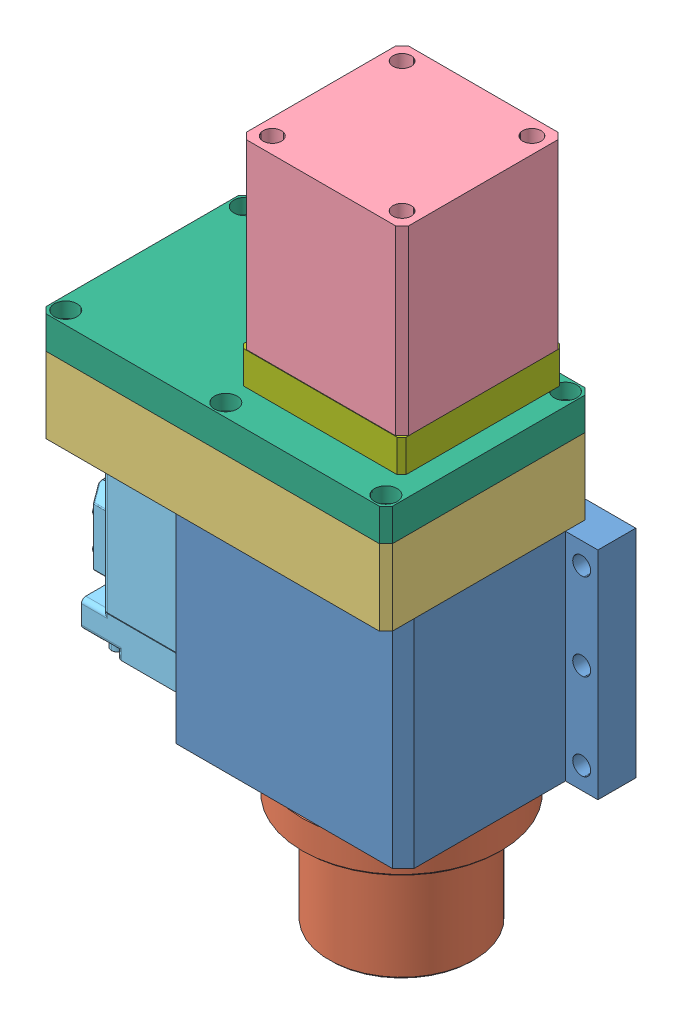
SolidWorks assembly DNM-65, configuration Default. Lengths in mm.
Overall size (189.85 314 100.5).
7 component instances, 7 part files, 18 mates.
Components (placement in the parent):
- DNM-65-1: DNM-65 [默认] at (14.1024 154.633 73.7637) size (140 100 92.5)
- DNM-65-M-1: DNM-65-M [默认] at (92.1024 -10.367 120.0137) x (1 0 0) z (0 1 0) size (92 92 220)
- DNM-65-C-1: DNM-65-C [默认] at (-20.8976 189.633 139.2637) x (1 0 0) z (0 -1 0) size (160 95 35)
- AT-1: AT [默认] at (54.6024 303.633 82.2637) x (0 0 1) z (0 -1 0) size (75 75 84)
- ser400w.step-1: ser400w.step [默认] at (-35.7442 129.1813 -8.3338) x (0 1 0) z (0 0 1) size (118.6 79.85 60.01)
- AD-1: AD [默认] at (-20.8976 204.633 174.2637) x (1 0 0) z (0 -1 0) size (160 95 15)
- SDATT-1: SDATT [默认] at (54.6024 219.633 157.5137) x (1 0 0) z (0 -1 0) size (75 75 15)
Mates (geometry in assembly coordinates):
- 同心1: concentric anti-aligned: cylinder of DNM-65-1 through (92.1024 54.633 120.0137) axis (0 1 0) radius 32.525; cylinder of DNM-65-M-1 through (92.1024 138.633 120.0137) axis (0 -1 0) radius 32.5
- 重合1: coincident anti-aligned: plane of DNM-65-1 through (14.1024 54.633 166.2637) normal (0 -1 0); plane of DNM-65-M-1 through (92.1024 54.633 120.0137) normal (0 1 0)
- 同心2: concentric aligned: circle of DNM-65-1; circle of DNM-65-M-1
- 平行1: parallel aligned: plane of DNM-65-C-1 through (-20.8976 154.633 139.2637) normal (-1 0 0); plane of ser400w.step-1 through (-15.8976 -1.8198 159.9887) normal (-1 0 0)
- 距离4: distance = 8 mm aligned: plane of DNM-65-1 through (14.1024 154.633 166.2637) normal (0 0 1); plane of DNM-65-C-1 through (47.1024 154.633 174.2637) normal (0 0 1)
- 重合19: coincident aligned: plane of DNM-65-1 through (139.1024 154.633 91.2637) normal (1 0 0); plane of DNM-65-C-1 through (139.1024 154.633 79.2637) normal (1 0 0)
- 距离5: distance = 0.025 mm anti-aligned: plane of DNM-65-1 through (44.1024 154.633 99.9637) normal (0 0 1); plane of ser400w.step-1 through (-15.8976 -1.8198 99.9887) normal (0 0 -1)
- 重合21: coincident anti-aligned: plane of DNM-65-1 through (44.1024 154.633 73.7637) normal (-1 0 0); plane of ser400w.step-1 through (44.1024 -1.8198 159.9887) normal (1 0 0)
- 距离7: distance = 9.5 mm aligned: plane of AT-1 through (129.6024 219.633 82.2637) normal (1 0 0); plane of DNM-65-C-1 through (139.1024 154.633 79.2637) normal (1 0 0)
- 重合26: coincident anti-aligned: plane of DNM-65-C-1 through (-20.8976 189.633 139.2637) normal (0 1 0); plane of AD-1 through (-20.8976 189.633 174.2637) normal (0 -1 0)
- 重合27: coincident aligned: plane of DNM-65-C-1 through (139.1024 154.633 79.2637) normal (1 0 0); plane of AD-1 through (139.1024 189.633 174.2637) normal (1 0 0)
- 重合28: coincident aligned: plane of DNM-65-C-1 through (139.1024 154.633 79.2637) normal (0 0 -1); plane of AD-1 through (-20.8976 189.633 79.2637) normal (0 0 -1)
- 距离8: distance = 3 mm aligned: plane of AD-1 through (-20.8976 189.633 79.2637) normal (0 0 -1); plane of AT-1 through (54.6024 219.633 82.2637) normal (0 0 -1)
- 重合30: coincident anti-aligned: plane of DNM-65-1 through (14.1024 154.633 166.2637) normal (0 1 0); plane of DNM-65-C-1 through (-20.8976 154.633 139.2637) normal (0 -1 0)
- 重合31: coincident anti-aligned: plane of AD-1 through (-20.8976 204.633 174.2637) normal (0 1 0); plane of SDATT-1 through (54.6024 204.633 157.5137) normal (0 -1 0)
- 同心3: concentric anti-aligned: cylinder of AD-1 through (92.1024 189.633 120.0137) axis (0 1 0) radius 12.5; cylinder of SDATT-1 through (92.1024 219.633 120.0137) axis (0 -1 0) radius 12.5
- 平行2: parallel aligned: plane of AD-1 through (139.1024 189.633 174.2637) normal (1 0 0); plane of SDATT-1 through (129.6024 204.633 157.5137) normal (1 0 0)
- 重合33: coincident anti-aligned: plane of AT-1 through (54.6024 219.633 82.2637) normal (0 -1 0); plane of SDATT-1 through (54.6024 219.633 157.5137) normal (0 1 0)
